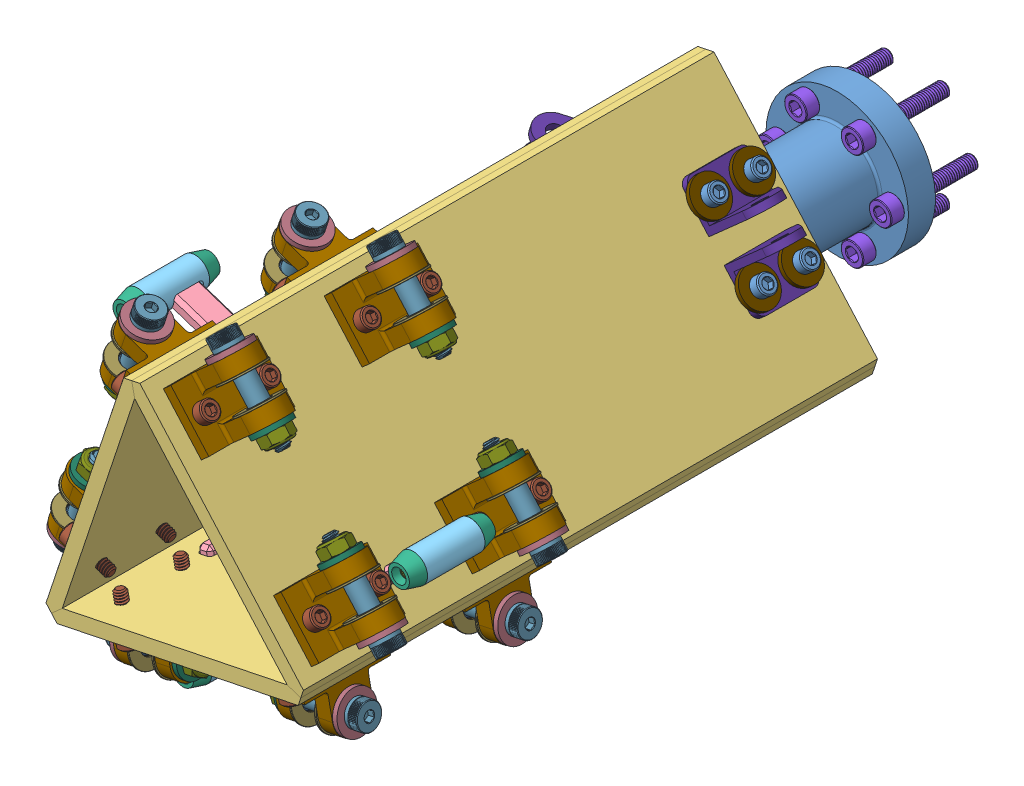
SolidWorks assembly Frame with Tabs and Links, configuration Default. Lengths in mm.
Overall size (158.73 160.79 334.34).
213 component instances, 19 part files, 45 mates.
Components (placement in the parent):
- Frame Assembly (FR)-1: Frame Assembly (FR) [Default] at (-29.1252 -2.2238 -96.7054) size (142.98 145.53 334.34)
  - Mounting Shaft (FR-1)-1: Mounting Shaft (FR-1) [Default] at (1.4417 19.9516 -46.3155) size (63 63 76)
  - Triangle (FR-2)-1: Triangle (FR-2) [Default] at (1.4417 19.9516 10.6845) x (0.979489 0.201496 0) z (0 0 1) size (101.6 87.99 6.35)
  - Frame Plate (FR-3)-1: Frame Plate (FR-3) [Default] at (23.3658 39.4335 112.2845) x (0.664246 -0.747514 0) z (0.747514 0.664246 0) size (112.6 254 6.35)
  - Frame Plate (FR-3)-2: Frame Plate (FR-3) [Default] at (-26.3922 29.1975 112.2845) x (0.315244 0.949011 0) z (-0.949011 0.315244 0) size (112.6 254 6.35)
  - Frame Plate (FR-3)-3: Frame Plate (FR-3) [Default] at (7.3514 -8.7763 112.2845) x (-0.979489 -0.201496 0) z (0.201496 -0.979489 0) size (112.6 254 6.35)
  - Bump Stop Assembly (BS)-1: Bump Stop Assembly (BS) [Default] at (-48.4512 43.2804 219.086) x (-0.315244 -0.949011 0) z (0.949011 -0.315244 0) size (14.59 38.1 45.39)
    - Bump Stop Bar (BS-1)-1: Bump Stop Bar (BS-1) [Default] at (-30.3388 9.583 -9.5512) size (6.22 12.57 38.1)
    - Bump Stop Rod (BS-2)-1: Bump Stop Rod (BS-2) [Default] at (-30.3388 18.7905 -9.5512) x (0 0 1) z (0 -1 0) size (12.7 12.7 25.4)
    - Bump Stop Bumper (MMC 9540K842)-1: Bump Stop Bumper (MMC 9540K842) [Default] at (-30.3388 18.7905 -9.5512) x (0.986856 0 -0.161605) z (0 1 0) size (12.7 12.7 6.35)
    - Bump Stop Bumper (MMC 9540K842)-2: Bump Stop Bumper (MMC 9540K842) [Default] at (-30.3388 -6.6095 -9.5512) x (1 0 0) z (0 -1 0) size (12.7 12.7 6.35)
    - Bump Stop Bolt (MMC 91306A256)-1: Bump Stop Bolt (MMC 91306A256) [91306A256] at (-30.3388 22.8482 -9.5512) x (1 0 0) z (0 1 0) size (6.05 6.05 8.36)
    - Bump Stop Bolt (MMC 91306A256)-2: Bump Stop Bolt (MMC 91306A256) [91306A256] at (-30.3388 -10.6671 -9.5512) x (1 0 0) z (0 -1 0) size (6.05 6.05 8.36)
  - Bump Stop Assembly (BS)-2: Bump Stop Assembly (BS) [Default] at (46.5915 51.4956 219.086) x (-0.664246 0.747514 0) z (-0.747514 -0.664246 0) size (14.59 38.1 45.39)
    - Bump Stop Bar (BS-1)-1: Bump Stop Bar (BS-1) [Default] at (-30.3388 9.583 -9.5512) size (6.22 12.57 38.1)
    - Bump Stop Rod (BS-2)-1: Bump Stop Rod (BS-2) [Default] at (-30.3388 18.7905 -9.5512) x (0 0 1) z (0 -1 0) size (12.7 12.7 25.4)
    - Bump Stop Bumper (MMC 9540K842)-1: Bump Stop Bumper (MMC 9540K842) [Default] at (-30.3388 18.7905 -9.5512) x (0.986856 0 -0.161605) z (0 1 0) size (12.7 12.7 6.35)
    - Bump Stop Bumper (MMC 9540K842)-2: Bump Stop Bumper (MMC 9540K842) [Default] at (-30.3388 -6.6095 -9.5512) x (1 0 0) z (0 -1 0) size (12.7 12.7 6.35)
    - Bump Stop Bolt (MMC 91306A256)-1: Bump Stop Bolt (MMC 91306A256) [91306A256] at (-30.3388 22.8482 -9.5512) x (1 0 0) z (0 1 0) size (6.05 6.05 8.36)
    - Bump Stop Bolt (MMC 91306A256)-2: Bump Stop Bolt (MMC 91306A256) [91306A256] at (-30.3388 -10.6671 -9.5512) x (1 0 0) z (0 -1 0) size (6.05 6.05 8.36)
  - Bump Stop Assembly (BS)-3: Bump Stop Assembly (BS) [Default] at (6.1847 -34.9214 219.086) x (0.979489 0.201496 0) z (-0.201496 0.979489 0) size (14.59 38.1 45.39)
    - Bump Stop Bar (BS-1)-1: Bump Stop Bar (BS-1) [Default] at (-30.3388 9.583 -9.5512) size (6.22 12.57 38.1)
    - Bump Stop Rod (BS-2)-1: Bump Stop Rod (BS-2) [Default] at (-30.3388 18.7905 -9.5512) x (0 0 1) z (0 -1 0) size (12.7 12.7 25.4)
    - Bump Stop Bumper (MMC 9540K842)-1: Bump Stop Bumper (MMC 9540K842) [Default] at (-30.3388 18.7905 -9.5512) x (0.986856 0 -0.161605) z (0 1 0) size (12.7 12.7 6.35)
    - Bump Stop Bumper (MMC 9540K842)-2: Bump Stop Bumper (MMC 9540K842) [Default] at (-30.3388 -6.6095 -9.5512) x (1 0 0) z (0 -1 0) size (12.7 12.7 6.35)
    - Bump Stop Bolt (MMC 91306A256)-1: Bump Stop Bolt (MMC 91306A256) [91306A256] at (-30.3388 22.8482 -9.5512) x (1 0 0) z (0 1 0) size (6.05 6.05 8.36)
    - Bump Stop Bolt (MMC 91306A256)-2: Bump Stop Bolt (MMC 91306A256) [91306A256] at (-30.3388 -10.6671 -9.5512) x (1 0 0) z (0 -1 0) size (6.05 6.05 8.36)
  - Bolt Circle Bolts (MMC 91290A334)-1: Bolt Circle Bolts (MMC 91290A334) [91290A334] at (26.4417 19.9516 -69.3155) x (-0.923728 -0.383049 0) z (0 0 -1) size (10 10 41.63)
  - Bolt Circle Bolts (MMC 91290A334)-2: Bolt Circle Bolts (MMC 91290A334) [91290A334] at (-23.5583 19.9516 -69.3155) x (-0.923728 -0.383049 0) z (0 0 -1) size (10 10 41.63)
  - Bolt Circle Bolts (MMC 91290A334)-3: Bolt Circle Bolts (MMC 91290A334) [91290A334] at (-11.0583 41.6022 -69.3155) x (-0.923728 -0.383049 0) z (0 0 -1) size (10 10 41.63)
  - Bolt Circle Bolts (MMC 91290A334)-4: Bolt Circle Bolts (MMC 91290A334) [91290A334] at (-11.0583 -1.6991 -69.3155) x (-0.923728 -0.383049 0) z (0 0 -1) size (10 10 41.63)
  - Bolt Circle Bolts (MMC 91290A334)-5: Bolt Circle Bolts (MMC 91290A334) [91290A334] at (13.9417 -1.6991 -69.3155) x (-0.923728 -0.383049 0) z (0 0 -1) size (10 10 41.63)
  - Bolt Circle Bolts (MMC 91290A334)-6: Bolt Circle Bolts (MMC 91290A334) [91290A334] at (13.9417 41.6022 -69.3155) x (-0.923728 -0.383049 0) z (0 0 -1) size (10 10 41.63)
- Tab Assembly-1: Tab Assembly [Default] at (-78.7846 -22.708 74.7515) x (-0.315244 -0.949011 0) z (-0.949011 0.315244 0) size (42.53 38.1 36.71)
  - Link Tab (LK-1)-1: Link Tab (LK-1) [Default] at (-17.7971 -3.9275 -0.0689) size (25.27 38.1 24.26)
  - Tab Sleeve Bushing (igus TSI-0506-04)-1: Tab Sleeve Bushing (igus TSI-0506-04) [Default] at (-5.1606 -3.9275 15.2981) x (0 0 1) z (-1 0 0) size (9.53 9.53 6.35)
  - Tab Sleeve Bushing (igus TSI-0506-04)-2: Tab Sleeve Bushing (igus TSI-0506-04) [Default] at (-30.4336 -3.9275 15.2981) x (0 -0.924225 -0.381849) z (1 0 0) size (9.53 9.53 6.35)
  - Tab Bolts (MMC 91251A244)-1: Tab Bolts (MMC 91251A244) [91251A244] at (-17.7971 9.4075 -11.4989) x (-0.923728 -0.383049 0) z (0 0 -1) size (7.92 7.92 21.32)
  - Tab Bolts (MMC 91251A244)-2: Tab Bolts (MMC 91251A244) [91251A244] at (-17.7971 -17.2625 -11.4989) x (-0.923728 -0.383049 0) z (0 0 -1) size (7.92 7.92 21.32)
  - Linkage Thrust Bearing (MSC 06455364)-1: Linkage Thrust Bearing (MSC 06455364) [Default] at (-12.5584 -3.9275 15.2981) x (0 0 -1) z (1 0 0) size (19.05 19.05 0.79)
  - Linkage Thrust Bearing (MSC 06455364)-2: Linkage Thrust Bearing (MSC 06455364) [Default] at (-23.8296 -3.9275 15.2981) x (0 0 -1) z (1 0 0) size (19.05 19.05 0.79)
  - SAE 0.3125 Washer (MMC 96659A107)-1: SAE 0.3125 Washer (MMC 96659A107) [96659A107] at (-3.1286 -3.9275 15.2981) x (0 1 0) z (0 0 1) size (17.46 2.03 17.46)
  - Link Pivot Shoulder Bolt (MMC 91259A583)-1: Link Pivot Shoulder Bolt (MMC 91259A583) [91259A583] at (-3.1286 -3.9275 15.2981) x (0 -1 0) z (0 0 1) size (11.11 42.53 11.11)
  - SAE 025 Washer (MMC 91083A029)-1: SAE 025 Washer (MMC 91083A029) [91083A029] at (-32.4656 -3.9275 15.2981) size (2.03 15.88 15.88)
  - Pivot Nylok (MMC 94945A205)-1: Pivot Nylok (MMC 94945A205) [94945A205] at (-32.4656 -3.9275 15.2981) x (0 1 0) z (0 0 1) size (11.11 5.35 12.83)
- Tab Assembly-2: Tab Assembly [Default] at (-44.4336 80.7024 66.8966) x (0.315244 0.949011 0) z (-0.949011 0.315244 0) size (42.53 38.1 36.71)
  - Link Tab (LK-1)-1: Link Tab (LK-1) [Default] at (-17.7971 -3.9275 -0.0689) size (25.27 38.1 24.26)
  - Tab Sleeve Bushing (igus TSI-0506-04)-1: Tab Sleeve Bushing (igus TSI-0506-04) [Default] at (-5.1606 -3.9275 15.2981) x (0 0 1) z (-1 0 0) size (9.53 9.53 6.35)
  - Tab Sleeve Bushing (igus TSI-0506-04)-2: Tab Sleeve Bushing (igus TSI-0506-04) [Default] at (-30.4336 -3.9275 15.2981) x (0 -0.924225 -0.381849) z (1 0 0) size (9.53 9.53 6.35)
  - Tab Bolts (MMC 91251A244)-1: Tab Bolts (MMC 91251A244) [91251A244] at (-17.7971 9.4075 -11.4989) x (-0.923728 -0.383049 0) z (0 0 -1) size (7.92 7.92 21.32)
  - Tab Bolts (MMC 91251A244)-2: Tab Bolts (MMC 91251A244) [91251A244] at (-17.7971 -17.2625 -11.4989) x (-0.923728 -0.383049 0) z (0 0 -1) size (7.92 7.92 21.32)
  - Linkage Thrust Bearing (MSC 06455364)-1: Linkage Thrust Bearing (MSC 06455364) [Default] at (-12.5584 -3.9275 15.2981) x (0 0 -1) z (1 0 0) size (19.05 19.05 0.79)
  - Linkage Thrust Bearing (MSC 06455364)-2: Linkage Thrust Bearing (MSC 06455364) [Default] at (-23.8296 -3.9275 15.2981) x (0 0 -1) z (1 0 0) size (19.05 19.05 0.79)
  - SAE 0.3125 Washer (MMC 96659A107)-1: SAE 0.3125 Washer (MMC 96659A107) [96659A107] at (-3.1286 -3.9275 15.2981) x (0 1 0) z (0 0 1) size (17.46 2.03 17.46)
  - Link Pivot Shoulder Bolt (MMC 91259A583)-1: Link Pivot Shoulder Bolt (MMC 91259A583) [91259A583] at (-3.1286 -3.9275 15.2981) x (0 -1 0) z (0 0 1) size (11.11 42.53 11.11)
  - SAE 025 Washer (MMC 91083A029)-1: SAE 025 Washer (MMC 91083A029) [91083A029] at (-32.4656 -3.9275 15.2981) size (2.03 15.88 15.88)
  - Pivot Nylok (MMC 94945A205)-1: Pivot Nylok (MMC 94945A205) [94945A205] at (-32.4656 -3.9275 15.2981) x (0 1 0) z (0 0 1) size (11.11 5.35 12.83)
- Tab Assembly-3: Tab Assembly [Default] at (-44.4336 80.7024 138.0166) x (0.315244 0.949011 0) z (-0.949011 0.315244 0) size (42.53 38.1 36.71)
  - Link Tab (LK-1)-1: Link Tab (LK-1) [Default] at (-17.7971 -3.9275 -0.0689) size (25.27 38.1 24.26)
  - Tab Sleeve Bushing (igus TSI-0506-04)-1: Tab Sleeve Bushing (igus TSI-0506-04) [Default] at (-5.1606 -3.9275 15.2981) x (0 0 1) z (-1 0 0) size (9.53 9.53 6.35)
  - Tab Sleeve Bushing (igus TSI-0506-04)-2: Tab Sleeve Bushing (igus TSI-0506-04) [Default] at (-30.4336 -3.9275 15.2981) x (0 -0.924225 -0.381849) z (1 0 0) size (9.53 9.53 6.35)
  - Tab Bolts (MMC 91251A244)-1: Tab Bolts (MMC 91251A244) [91251A244] at (-17.7971 9.4075 -11.4989) x (-0.923728 -0.383049 0) z (0 0 -1) size (7.92 7.92 21.32)
  - Tab Bolts (MMC 91251A244)-2: Tab Bolts (MMC 91251A244) [91251A244] at (-17.7971 -17.2625 -11.4989) x (-0.923728 -0.383049 0) z (0 0 -1) size (7.92 7.92 21.32)
  - Linkage Thrust Bearing (MSC 06455364)-1: Linkage Thrust Bearing (MSC 06455364) [Default] at (-12.5584 -3.9275 15.2981) x (0 0 -1) z (1 0 0) size (19.05 19.05 0.79)
  - Linkage Thrust Bearing (MSC 06455364)-2: Linkage Thrust Bearing (MSC 06455364) [Default] at (-23.8296 -3.9275 15.2981) x (0 0 -1) z (1 0 0) size (19.05 19.05 0.79)
  - SAE 0.3125 Washer (MMC 96659A107)-1: SAE 0.3125 Washer (MMC 96659A107) [96659A107] at (-3.1286 -3.9275 15.2981) x (0 1 0) z (0 0 1) size (17.46 2.03 17.46)
  - Link Pivot Shoulder Bolt (MMC 91259A583)-1: Link Pivot Shoulder Bolt (MMC 91259A583) [91259A583] at (-3.1286 -3.9275 15.2981) x (0 -1 0) z (0 0 1) size (11.11 42.53 11.11)
  - SAE 025 Washer (MMC 91083A029)-1: SAE 025 Washer (MMC 91083A029) [91083A029] at (-32.4656 -3.9275 15.2981) size (2.03 15.88 15.88)
  - Pivot Nylok (MMC 94945A205)-1: Pivot Nylok (MMC 94945A205) [94945A205] at (-32.4656 -3.9275 15.2981) x (0 1 0) z (0 0 1) size (11.11 5.35 12.83)
- Tab Assembly-4: Tab Assembly [Default] at (-78.7846 -22.708 145.8715) x (-0.315244 -0.949011 0) z (-0.949011 0.315244 0) size (42.53 38.1 36.71)
  - Link Tab (LK-1)-1: Link Tab (LK-1) [Default] at (-17.7971 -3.9275 -0.0689) size (25.27 38.1 24.26)
  - Tab Sleeve Bushing (igus TSI-0506-04)-1: Tab Sleeve Bushing (igus TSI-0506-04) [Default] at (-5.1606 -3.9275 15.2981) x (0 0 1) z (-1 0 0) size (9.53 9.53 6.35)
  - Tab Sleeve Bushing (igus TSI-0506-04)-2: Tab Sleeve Bushing (igus TSI-0506-04) [Default] at (-30.4336 -3.9275 15.2981) x (0 -0.924225 -0.381849) z (1 0 0) size (9.53 9.53 6.35)
  - Tab Bolts (MMC 91251A244)-1: Tab Bolts (MMC 91251A244) [91251A244] at (-17.7971 9.4075 -11.4989) x (-0.923728 -0.383049 0) z (0 0 -1) size (7.92 7.92 21.32)
  - Tab Bolts (MMC 91251A244)-2: Tab Bolts (MMC 91251A244) [91251A244] at (-17.7971 -17.2625 -11.4989) x (-0.923728 -0.383049 0) z (0 0 -1) size (7.92 7.92 21.32)
  - Linkage Thrust Bearing (MSC 06455364)-1: Linkage Thrust Bearing (MSC 06455364) [Default] at (-12.5584 -3.9275 15.2981) x (0 0 -1) z (1 0 0) size (19.05 19.05 0.79)
  - Linkage Thrust Bearing (MSC 06455364)-2: Linkage Thrust Bearing (MSC 06455364) [Default] at (-23.8296 -3.9275 15.2981) x (0 0 -1) z (1 0 0) size (19.05 19.05 0.79)
  - SAE 0.3125 Washer (MMC 96659A107)-1: SAE 0.3125 Washer (MMC 96659A107) [96659A107] at (-3.1286 -3.9275 15.2981) x (0 1 0) z (0 0 1) size (17.46 2.03 17.46)
  - Link Pivot Shoulder Bolt (MMC 91259A583)-1: Link Pivot Shoulder Bolt (MMC 91259A583) [91259A583] at (-3.1286 -3.9275 15.2981) x (0 -1 0) z (0 0 1) size (11.11 42.53 11.11)
  - SAE 025 Washer (MMC 91083A029)-1: SAE 025 Washer (MMC 91083A029) [91083A029] at (-32.4656 -3.9275 15.2981) size (2.03 15.88 15.88)
  - Pivot Nylok (MMC 94945A205)-1: Pivot Nylok (MMC 94945A205) [94945A205] at (-32.4656 -3.9275 15.2981) x (0 1 0) z (0 0 1) size (11.11 5.35 12.83)
- Tab Assembly-5: Tab Assembly [Default] at (35.2291 0.7464 66.8966) x (0.664246 -0.747514 0) z (0.747514 0.664246 0) size (42.53 38.1 36.71)
  - Link Tab (LK-1)-1: Link Tab (LK-1) [Default] at (-17.7971 -3.9275 -0.0689) size (25.27 38.1 24.26)
  - Tab Sleeve Bushing (igus TSI-0506-04)-1: Tab Sleeve Bushing (igus TSI-0506-04) [Default] at (-5.1606 -3.9275 15.2981) x (0 0 1) z (-1 0 0) size (9.53 9.53 6.35)
  - Tab Sleeve Bushing (igus TSI-0506-04)-2: Tab Sleeve Bushing (igus TSI-0506-04) [Default] at (-30.4336 -3.9275 15.2981) x (0 -0.924225 -0.381849) z (1 0 0) size (9.53 9.53 6.35)
  - Tab Bolts (MMC 91251A244)-1: Tab Bolts (MMC 91251A244) [91251A244] at (-17.7971 9.4075 -11.4989) x (-0.923728 -0.383049 0) z (0 0 -1) size (7.92 7.92 21.32)
  - Tab Bolts (MMC 91251A244)-2: Tab Bolts (MMC 91251A244) [91251A244] at (-17.7971 -17.2625 -11.4989) x (-0.923728 -0.383049 0) z (0 0 -1) size (7.92 7.92 21.32)
  - Linkage Thrust Bearing (MSC 06455364)-1: Linkage Thrust Bearing (MSC 06455364) [Default] at (-12.5584 -3.9275 15.2981) x (0 0 -1) z (1 0 0) size (19.05 19.05 0.79)
  - Linkage Thrust Bearing (MSC 06455364)-2: Linkage Thrust Bearing (MSC 06455364) [Default] at (-23.8296 -3.9275 15.2981) x (0 0 -1) z (1 0 0) size (19.05 19.05 0.79)
  - SAE 0.3125 Washer (MMC 96659A107)-1: SAE 0.3125 Washer (MMC 96659A107) [96659A107] at (-3.1286 -3.9275 15.2981) x (0 1 0) z (0 0 1) size (17.46 2.03 17.46)
  - Link Pivot Shoulder Bolt (MMC 91259A583)-1: Link Pivot Shoulder Bolt (MMC 91259A583) [91259A583] at (-3.1286 -3.9275 15.2981) x (0 -1 0) z (0 0 1) size (11.11 42.53 11.11)
  - SAE 025 Washer (MMC 91083A029)-1: SAE 025 Washer (MMC 91083A029) [91083A029] at (-32.4656 -3.9275 15.2981) size (2.03 15.88 15.88)
  - Pivot Nylok (MMC 94945A205)-1: Pivot Nylok (MMC 94945A205) [94945A205] at (-32.4656 -3.9275 15.2981) x (0 1 0) z (0 0 1) size (11.11 5.35 12.83)
- Tab Assembly-6: Tab Assembly [Default] at (-37.1514 82.2005 74.7515) x (-0.664246 0.747514 0) z (0.747514 0.664246 0) size (42.53 38.1 36.71)
  - Link Tab (LK-1)-1: Link Tab (LK-1) [Default] at (-17.7971 -3.9275 -0.0689) size (25.27 38.1 24.26)
  - Tab Sleeve Bushing (igus TSI-0506-04)-1: Tab Sleeve Bushing (igus TSI-0506-04) [Default] at (-5.1606 -3.9275 15.2981) x (0 0 1) z (-1 0 0) size (9.53 9.53 6.35)
  - Tab Sleeve Bushing (igus TSI-0506-04)-2: Tab Sleeve Bushing (igus TSI-0506-04) [Default] at (-30.4336 -3.9275 15.2981) x (0 -0.924225 -0.381849) z (1 0 0) size (9.53 9.53 6.35)
  - Tab Bolts (MMC 91251A244)-1: Tab Bolts (MMC 91251A244) [91251A244] at (-17.7971 9.4075 -11.4989) x (-0.923728 -0.383049 0) z (0 0 -1) size (7.92 7.92 21.32)
  - Tab Bolts (MMC 91251A244)-2: Tab Bolts (MMC 91251A244) [91251A244] at (-17.7971 -17.2625 -11.4989) x (-0.923728 -0.383049 0) z (0 0 -1) size (7.92 7.92 21.32)
  - Linkage Thrust Bearing (MSC 06455364)-1: Linkage Thrust Bearing (MSC 06455364) [Default] at (-12.5584 -3.9275 15.2981) x (0 0 -1) z (1 0 0) size (19.05 19.05 0.79)
  - Linkage Thrust Bearing (MSC 06455364)-2: Linkage Thrust Bearing (MSC 06455364) [Default] at (-23.8296 -3.9275 15.2981) x (0 0 -1) z (1 0 0) size (19.05 19.05 0.79)
  - SAE 0.3125 Washer (MMC 96659A107)-1: SAE 0.3125 Washer (MMC 96659A107) [96659A107] at (-3.1286 -3.9275 15.2981) x (0 1 0) z (0 0 1) size (17.46 2.03 17.46)
  - Link Pivot Shoulder Bolt (MMC 91259A583)-1: Link Pivot Shoulder Bolt (MMC 91259A583) [91259A583] at (-3.1286 -3.9275 15.2981) x (0 -1 0) z (0 0 1) size (11.11 42.53 11.11)
  - SAE 025 Washer (MMC 91083A029)-1: SAE 025 Washer (MMC 91083A029) [91083A029] at (-32.4656 -3.9275 15.2981) size (2.03 15.88 15.88)
  - Pivot Nylok (MMC 94945A205)-1: Pivot Nylok (MMC 94945A205) [94945A205] at (-32.4656 -3.9275 15.2981) x (0 1 0) z (0 0 1) size (11.11 5.35 12.83)
- Tab Assembly-7: Tab Assembly [Default] at (35.2291 0.7464 138.0166) x (0.664246 -0.747514 0) z (0.747514 0.664246 0) size (42.53 38.1 36.71)
  - Link Tab (LK-1)-1: Link Tab (LK-1) [Default] at (-17.7971 -3.9275 -0.0689) size (25.27 38.1 24.26)
  - Tab Sleeve Bushing (igus TSI-0506-04)-1: Tab Sleeve Bushing (igus TSI-0506-04) [Default] at (-5.1606 -3.9275 15.2981) x (0 0 1) z (-1 0 0) size (9.53 9.53 6.35)
  - Tab Sleeve Bushing (igus TSI-0506-04)-2: Tab Sleeve Bushing (igus TSI-0506-04) [Default] at (-30.4336 -3.9275 15.2981) x (0 -0.924225 -0.381849) z (1 0 0) size (9.53 9.53 6.35)
  - Tab Bolts (MMC 91251A244)-1: Tab Bolts (MMC 91251A244) [91251A244] at (-17.7971 9.4075 -11.4989) x (-0.923728 -0.383049 0) z (0 0 -1) size (7.92 7.92 21.32)
  - Tab Bolts (MMC 91251A244)-2: Tab Bolts (MMC 91251A244) [91251A244] at (-17.7971 -17.2625 -11.4989) x (-0.923728 -0.383049 0) z (0 0 -1) size (7.92 7.92 21.32)
  - Linkage Thrust Bearing (MSC 06455364)-1: Linkage Thrust Bearing (MSC 06455364) [Default] at (-12.5584 -3.9275 15.2981) x (0 0 -1) z (1 0 0) size (19.05 19.05 0.79)
  - Linkage Thrust Bearing (MSC 06455364)-2: Linkage Thrust Bearing (MSC 06455364) [Default] at (-23.8296 -3.9275 15.2981) x (0 0 -1) z (1 0 0) size (19.05 19.05 0.79)
  - SAE 0.3125 Washer (MMC 96659A107)-1: SAE 0.3125 Washer (MMC 96659A107) [96659A107] at (-3.1286 -3.9275 15.2981) x (0 1 0) z (0 0 1) size (17.46 2.03 17.46)
  - Link Pivot Shoulder Bolt (MMC 91259A583)-1: Link Pivot Shoulder Bolt (MMC 91259A583) [91259A583] at (-3.1286 -3.9275 15.2981) x (0 -1 0) z (0 0 1) size (11.11 42.53 11.11)
  - SAE 025 Washer (MMC 91083A029)-1: SAE 025 Washer (MMC 91083A029) [91083A029] at (-32.4656 -3.9275 15.2981) size (2.03 15.88 15.88)
  - Pivot Nylok (MMC 94945A205)-1: Pivot Nylok (MMC 94945A205) [94945A205] at (-32.4656 -3.9275 15.2981) x (0 1 0) z (0 0 1) size (11.11 5.35 12.83)
- Tab Assembly-8: Tab Assembly [Default] at (-37.1514 82.2005 145.8715) x (-0.664246 0.747514 0) z (0.747514 0.664246 0) size (42.53 38.1 36.71)
  - Link Tab (LK-1)-1: Link Tab (LK-1) [Default] at (-17.7971 -3.9275 -0.0689) size (25.27 38.1 24.26)
  - Tab Sleeve Bushing (igus TSI-0506-04)-1: Tab Sleeve Bushing (igus TSI-0506-04) [Default] at (-5.1606 -3.9275 15.2981) x (0 0 1) z (-1 0 0) size (9.53 9.53 6.35)
  - Tab Sleeve Bushing (igus TSI-0506-04)-2: Tab Sleeve Bushing (igus TSI-0506-04) [Default] at (-30.4336 -3.9275 15.2981) x (0 -0.924225 -0.381849) z (1 0 0) size (9.53 9.53 6.35)
  - Tab Bolts (MMC 91251A244)-1: Tab Bolts (MMC 91251A244) [91251A244] at (-17.7971 9.4075 -11.4989) x (-0.923728 -0.383049 0) z (0 0 -1) size (7.92 7.92 21.32)
  - Tab Bolts (MMC 91251A244)-2: Tab Bolts (MMC 91251A244) [91251A244] at (-17.7971 -17.2625 -11.4989) x (-0.923728 -0.383049 0) z (0 0 -1) size (7.92 7.92 21.32)
  - Linkage Thrust Bearing (MSC 06455364)-1: Linkage Thrust Bearing (MSC 06455364) [Default] at (-12.5584 -3.9275 15.2981) x (0 0 -1) z (1 0 0) size (19.05 19.05 0.79)
  - Linkage Thrust Bearing (MSC 06455364)-2: Linkage Thrust Bearing (MSC 06455364) [Default] at (-23.8296 -3.9275 15.2981) x (0 0 -1) z (1 0 0) size (19.05 19.05 0.79)
  - SAE 0.3125 Washer (MMC 96659A107)-1: SAE 0.3125 Washer (MMC 96659A107) [96659A107] at (-3.1286 -3.9275 15.2981) x (0 1 0) z (0 0 1) size (17.46 2.03 17.46)
  - Link Pivot Shoulder Bolt (MMC 91259A583)-1: Link Pivot Shoulder Bolt (MMC 91259A583) [91259A583] at (-3.1286 -3.9275 15.2981) x (0 -1 0) z (0 0 1) size (11.11 42.53 11.11)
  - SAE 025 Washer (MMC 91083A029)-1: SAE 025 Washer (MMC 91083A029) [91083A029] at (-32.4656 -3.9275 15.2981) size (2.03 15.88 15.88)
  - Pivot Nylok (MMC 94945A205)-1: Pivot Nylok (MMC 94945A205) [94945A205] at (-32.4656 -3.9275 15.2981) x (0 1 0) z (0 0 1) size (11.11 5.35 12.83)
- Tab Assembly-9: Tab Assembly [Default] at (32.8854 -6.3091 145.8715) x (0.979489 0.201496 0) z (0.201496 -0.979489 0) size (42.53 38.1 36.71)
  - Link Tab (LK-1)-1: Link Tab (LK-1) [Default] at (-17.7971 -3.9275 -0.0689) size (25.27 38.1 24.26)
  - Tab Sleeve Bushing (igus TSI-0506-04)-1: Tab Sleeve Bushing (igus TSI-0506-04) [Default] at (-5.1606 -3.9275 15.2981) x (0 0 1) z (-1 0 0) size (9.53 9.53 6.35)
  - Tab Sleeve Bushing (igus TSI-0506-04)-2: Tab Sleeve Bushing (igus TSI-0506-04) [Default] at (-30.4336 -3.9275 15.2981) x (0 -0.924225 -0.381849) z (1 0 0) size (9.53 9.53 6.35)
  - Tab Bolts (MMC 91251A244)-1: Tab Bolts (MMC 91251A244) [91251A244] at (-17.7971 9.4075 -11.4989) x (-0.923728 -0.383049 0) z (0 0 -1) size (7.92 7.92 21.32)
  - Tab Bolts (MMC 91251A244)-2: Tab Bolts (MMC 91251A244) [91251A244] at (-17.7971 -17.2625 -11.4989) x (-0.923728 -0.383049 0) z (0 0 -1) size (7.92 7.92 21.32)
  - Linkage Thrust Bearing (MSC 06455364)-1: Linkage Thrust Bearing (MSC 06455364) [Default] at (-12.5584 -3.9275 15.2981) x (0 0 -1) z (1 0 0) size (19.05 19.05 0.79)
  - Linkage Thrust Bearing (MSC 06455364)-2: Linkage Thrust Bearing (MSC 06455364) [Default] at (-23.8296 -3.9275 15.2981) x (0 0 -1) z (1 0 0) size (19.05 19.05 0.79)
  - SAE 0.3125 Washer (MMC 96659A107)-1: SAE 0.3125 Washer (MMC 96659A107) [96659A107] at (-3.1286 -3.9275 15.2981) x (0 1 0) z (0 0 1) size (17.46 2.03 17.46)
  - Link Pivot Shoulder Bolt (MMC 91259A583)-1: Link Pivot Shoulder Bolt (MMC 91259A583) [91259A583] at (-3.1286 -3.9275 15.2981) x (0 -1 0) z (0 0 1) size (11.11 42.53 11.11)
  - SAE 025 Washer (MMC 91083A029)-1: SAE 025 Washer (MMC 91083A029) [91083A029] at (-32.4656 -3.9275 15.2981) size (2.03 15.88 15.88)
  - Pivot Nylok (MMC 94945A205)-1: Pivot Nylok (MMC 94945A205) [94945A205] at (-32.4656 -3.9275 15.2981) x (0 1 0) z (0 0 1) size (11.11 5.35 12.83)
- Tab Assembly-10: Tab Assembly [Default] at (-73.8462 -28.2655 66.8966) x (-0.979489 -0.201496 0) z (0.201496 -0.979489 0) size (42.53 38.1 36.71)
  - Link Tab (LK-1)-1: Link Tab (LK-1) [Default] at (-17.7971 -3.9275 -0.0689) size (25.27 38.1 24.26)
  - Tab Sleeve Bushing (igus TSI-0506-04)-1: Tab Sleeve Bushing (igus TSI-0506-04) [Default] at (-5.1606 -3.9275 15.2981) x (0 0 1) z (-1 0 0) size (9.53 9.53 6.35)
  - Tab Sleeve Bushing (igus TSI-0506-04)-2: Tab Sleeve Bushing (igus TSI-0506-04) [Default] at (-30.4336 -3.9275 15.2981) x (0 -0.924225 -0.381849) z (1 0 0) size (9.53 9.53 6.35)
  - Tab Bolts (MMC 91251A244)-1: Tab Bolts (MMC 91251A244) [91251A244] at (-17.7971 9.4075 -11.4989) x (-0.923728 -0.383049 0) z (0 0 -1) size (7.92 7.92 21.32)
  - Tab Bolts (MMC 91251A244)-2: Tab Bolts (MMC 91251A244) [91251A244] at (-17.7971 -17.2625 -11.4989) x (-0.923728 -0.383049 0) z (0 0 -1) size (7.92 7.92 21.32)
  - Linkage Thrust Bearing (MSC 06455364)-1: Linkage Thrust Bearing (MSC 06455364) [Default] at (-12.5584 -3.9275 15.2981) x (0 0 -1) z (1 0 0) size (19.05 19.05 0.79)
  - Linkage Thrust Bearing (MSC 06455364)-2: Linkage Thrust Bearing (MSC 06455364) [Default] at (-23.8296 -3.9275 15.2981) x (0 0 -1) z (1 0 0) size (19.05 19.05 0.79)
  - SAE 0.3125 Washer (MMC 96659A107)-1: SAE 0.3125 Washer (MMC 96659A107) [96659A107] at (-3.1286 -3.9275 15.2981) x (0 1 0) z (0 0 1) size (17.46 2.03 17.46)
  - Link Pivot Shoulder Bolt (MMC 91259A583)-1: Link Pivot Shoulder Bolt (MMC 91259A583) [91259A583] at (-3.1286 -3.9275 15.2981) x (0 -1 0) z (0 0 1) size (11.11 42.53 11.11)
  - SAE 025 Washer (MMC 91083A029)-1: SAE 025 Washer (MMC 91083A029) [91083A029] at (-32.4656 -3.9275 15.2981) size (2.03 15.88 15.88)
  - Pivot Nylok (MMC 94945A205)-1: Pivot Nylok (MMC 94945A205) [94945A205] at (-32.4656 -3.9275 15.2981) x (0 1 0) z (0 0 1) size (11.11 5.35 12.83)
- Tab Assembly-11: Tab Assembly [Default] at (-73.8462 -28.2655 138.0166) x (-0.979489 -0.201496 0) z (0.201496 -0.979489 0) size (42.53 38.1 36.71)
  - Link Tab (LK-1)-1: Link Tab (LK-1) [Default] at (-17.7971 -3.9275 -0.0689) size (25.27 38.1 24.26)
  - Tab Sleeve Bushing (igus TSI-0506-04)-1: Tab Sleeve Bushing (igus TSI-0506-04) [Default] at (-5.1606 -3.9275 15.2981) x (0 0 1) z (-1 0 0) size (9.53 9.53 6.35)
  - Tab Sleeve Bushing (igus TSI-0506-04)-2: Tab Sleeve Bushing (igus TSI-0506-04) [Default] at (-30.4336 -3.9275 15.2981) x (0 -0.924225 -0.381849) z (1 0 0) size (9.53 9.53 6.35)
  - Tab Bolts (MMC 91251A244)-1: Tab Bolts (MMC 91251A244) [91251A244] at (-17.7971 9.4075 -11.4989) x (-0.923728 -0.383049 0) z (0 0 -1) size (7.92 7.92 21.32)
  - Tab Bolts (MMC 91251A244)-2: Tab Bolts (MMC 91251A244) [91251A244] at (-17.7971 -17.2625 -11.4989) x (-0.923728 -0.383049 0) z (0 0 -1) size (7.92 7.92 21.32)
  - Linkage Thrust Bearing (MSC 06455364)-1: Linkage Thrust Bearing (MSC 06455364) [Default] at (-12.5584 -3.9275 15.2981) x (0 0 -1) z (1 0 0) size (19.05 19.05 0.79)
  - Linkage Thrust Bearing (MSC 06455364)-2: Linkage Thrust Bearing (MSC 06455364) [Default] at (-23.8296 -3.9275 15.2981) x (0 0 -1) z (1 0 0) size (19.05 19.05 0.79)
  - SAE 0.3125 Washer (MMC 96659A107)-1: SAE 0.3125 Washer (MMC 96659A107) [96659A107] at (-3.1286 -3.9275 15.2981) x (0 1 0) z (0 0 1) size (17.46 2.03 17.46)
  - Link Pivot Shoulder Bolt (MMC 91259A583)-1: Link Pivot Shoulder Bolt (MMC 91259A583) [91259A583] at (-3.1286 -3.9275 15.2981) x (0 -1 0) z (0 0 1) size (11.11 42.53 11.11)
  - SAE 025 Washer (MMC 91083A029)-1: SAE 025 Washer (MMC 91083A029) [91083A029] at (-32.4656 -3.9275 15.2981) size (2.03 15.88 15.88)
  - Pivot Nylok (MMC 94945A205)-1: Pivot Nylok (MMC 94945A205) [94945A205] at (-32.4656 -3.9275 15.2981) x (0 1 0) z (0 0 1) size (11.11 5.35 12.83)
- Tab Assembly-12: Tab Assembly [Default] at (32.8854 -6.3091 74.7515) x (0.979489 0.201496 0) z (0.201496 -0.979489 0) size (42.53 38.1 36.71)
  - Link Tab (LK-1)-1: Link Tab (LK-1) [Default] at (-17.7971 -3.9275 -0.0689) size (25.27 38.1 24.26)
  - Tab Sleeve Bushing (igus TSI-0506-04)-1: Tab Sleeve Bushing (igus TSI-0506-04) [Default] at (-5.1606 -3.9275 15.2981) x (0 0 1) z (-1 0 0) size (9.53 9.53 6.35)
  - Tab Sleeve Bushing (igus TSI-0506-04)-2: Tab Sleeve Bushing (igus TSI-0506-04) [Default] at (-30.4336 -3.9275 15.2981) x (0 -0.924225 -0.381849) z (1 0 0) size (9.53 9.53 6.35)
  - Tab Bolts (MMC 91251A244)-1: Tab Bolts (MMC 91251A244) [91251A244] at (-17.7971 9.4075 -11.4989) x (-0.923728 -0.383049 0) z (0 0 -1) size (7.92 7.92 21.32)
  - Tab Bolts (MMC 91251A244)-2: Tab Bolts (MMC 91251A244) [91251A244] at (-17.7971 -17.2625 -11.4989) x (-0.923728 -0.383049 0) z (0 0 -1) size (7.92 7.92 21.32)
  - Linkage Thrust Bearing (MSC 06455364)-1: Linkage Thrust Bearing (MSC 06455364) [Default] at (-12.5584 -3.9275 15.2981) x (0 0 -1) z (1 0 0) size (19.05 19.05 0.79)
  - Linkage Thrust Bearing (MSC 06455364)-2: Linkage Thrust Bearing (MSC 06455364) [Default] at (-23.8296 -3.9275 15.2981) x (0 0 -1) z (1 0 0) size (19.05 19.05 0.79)
  - SAE 0.3125 Washer (MMC 96659A107)-1: SAE 0.3125 Washer (MMC 96659A107) [96659A107] at (-3.1286 -3.9275 15.2981) x (0 1 0) z (0 0 1) size (17.46 2.03 17.46)
  - Link Pivot Shoulder Bolt (MMC 91259A583)-1: Link Pivot Shoulder Bolt (MMC 91259A583) [91259A583] at (-3.1286 -3.9275 15.2981) x (0 -1 0) z (0 0 1) size (11.11 42.53 11.11)
  - SAE 025 Washer (MMC 91083A029)-1: SAE 025 Washer (MMC 91083A029) [91083A029] at (-32.4656 -3.9275 15.2981) size (2.03 15.88 15.88)
  - Pivot Nylok (MMC 94945A205)-1: Pivot Nylok (MMC 94945A205) [94945A205] at (-32.4656 -3.9275 15.2981) x (0 1 0) z (0 0 1) size (11.11 5.35 12.83)
- Frame Side Bracket Assembly-1: Frame Side Bracket Assembly [Default] at (-82.4621 -4.4954 -48.6466) x (-0.315244 -0.949011 0) z (0 0 -1) size (50.29 41.41 34.93)
  - Frame Side Brackets (NCM-PC075)-1: Frame Side Brackets (NCM-PC075) [NCM-PC075] at (-38.3587 -9.3003 16.2923) size (50.29 30.23 27.94)
    - NCM-PC075_NCMP-C-Bracket-1: NCM-PC075_NCMP-C-Bracket [075F] at (5.08 0 0) size (20.07 30.23 27.94)
    - NCM-PC075_NCMP-C-Bracket-2: NCM-PC075_NCMP-C-Bracket [075R] at (-5.08 0 0) x (-1 0 0) z (0 0 -1) size (20.07 30.23 27.94)
  - SAE 0.25 Washer (MMC 91083A029)-1: SAE 0.25 Washer (MMC 91083A029) [91083A029] at (-54.6147 -4.2203 6.8943) x (0 -1 0) z (0 0 1) size (2.03 15.88 15.88)
  - SAE 0.25 Washer (MMC 91083A029)-2: SAE 0.25 Washer (MMC 91083A029) [91083A029] at (-54.6147 -4.2203 25.9443) x (0 -1 0) z (0 0 1) size (2.03 15.88 15.88)
  - SAE 0.25 Washer (MMC 91083A029)-3: SAE 0.25 Washer (MMC 91083A029) [91083A029] at (-22.1027 -4.2203 6.8943) x (0 -1 0) z (0 0 1) size (2.03 15.88 15.88)
  - SAE 0.25 Washer (MMC 91083A029)-4: SAE 0.25 Washer (MMC 91083A029) [91083A029] at (-22.1027 -4.2203 25.9443) x (0 -1 0) z (0 0 1) size (2.03 15.88 15.88)
  - Tab Bolt (MMC 91251A244)-1: Tab Bolt (MMC 91251A244) [91251A244] at (-22.1027 -20.0953 25.9443) x (1 0 0) z (0 -1 0) size (7.92 7.92 21.32)
  - Tab Bolt (MMC 91251A244)-2: Tab Bolt (MMC 91251A244) [91251A244] at (-22.1027 -20.0953 6.8943) x (1 0 0) z (0 -1 0) size (7.92 7.92 21.32)
  - Tab Bolt (MMC 91251A244)-3: Tab Bolt (MMC 91251A244) [91251A244] at (-54.6147 -20.0953 25.9443) x (1 0 0) z (0 -1 0) size (7.92 7.92 21.32)
  - Tab Bolt (MMC 91251A244)-4: Tab Bolt (MMC 91251A244) [91251A244] at (-54.6147 -20.0953 6.8943) x (1 0 0) z (0 -1 0) size (7.92 7.92 21.32)
- Frame Side Bracket Assembly-2: Frame Side Bracket Assembly [Default] at (-19.5401 76.2791 -48.6466) x (-0.664246 0.747514 0) z (0 0 -1) size (50.29 41.41 34.93)
  - Frame Side Brackets (NCM-PC075)-1: Frame Side Brackets (NCM-PC075) [NCM-PC075] at (-38.3587 -9.3003 16.2923) size (50.29 30.23 27.94)
    - NCM-PC075_NCMP-C-Bracket-1: NCM-PC075_NCMP-C-Bracket [075F] at (5.08 0 0) size (20.07 30.23 27.94)
    - NCM-PC075_NCMP-C-Bracket-2: NCM-PC075_NCMP-C-Bracket [075R] at (-5.08 0 0) x (-1 0 0) z (0 0 -1) size (20.07 30.23 27.94)
  - SAE 0.25 Washer (MMC 91083A029)-1: SAE 0.25 Washer (MMC 91083A029) [91083A029] at (-54.6147 -4.2203 6.8943) x (0 -1 0) z (0 0 1) size (2.03 15.88 15.88)
  - SAE 0.25 Washer (MMC 91083A029)-2: SAE 0.25 Washer (MMC 91083A029) [91083A029] at (-54.6147 -4.2203 25.9443) x (0 -1 0) z (0 0 1) size (2.03 15.88 15.88)
  - SAE 0.25 Washer (MMC 91083A029)-3: SAE 0.25 Washer (MMC 91083A029) [91083A029] at (-22.1027 -4.2203 6.8943) x (0 -1 0) z (0 0 1) size (2.03 15.88 15.88)
  - SAE 0.25 Washer (MMC 91083A029)-4: SAE 0.25 Washer (MMC 91083A029) [91083A029] at (-22.1027 -4.2203 25.9443) x (0 -1 0) z (0 0 1) size (2.03 15.88 15.88)
  - Tab Bolt (MMC 91251A244)-1: Tab Bolt (MMC 91251A244) [91251A244] at (-22.1027 -20.0953 25.9443) x (1 0 0) z (0 -1 0) size (7.92 7.92 21.32)
  - Tab Bolt (MMC 91251A244)-2: Tab Bolt (MMC 91251A244) [91251A244] at (-22.1027 -20.0953 6.8943) x (1 0 0) z (0 -1 0) size (7.92 7.92 21.32)
  - Tab Bolt (MMC 91251A244)-3: Tab Bolt (MMC 91251A244) [91251A244] at (-54.6147 -20.0953 25.9443) x (1 0 0) z (0 -1 0) size (7.92 7.92 21.32)
  - Tab Bolt (MMC 91251A244)-4: Tab Bolt (MMC 91251A244) [91251A244] at (-54.6147 -20.0953 6.8943) x (1 0 0) z (0 -1 0) size (7.92 7.92 21.32)
- Frame Side Bracket Assembly-3: Frame Side Bracket Assembly [Default] at (18.9517 -18.6003 -48.6466) x (0.979489 0.201496 0) z (0 0 -1) size (50.29 41.41 34.93)
  - Frame Side Brackets (NCM-PC075)-1: Frame Side Brackets (NCM-PC075) [NCM-PC075] at (-38.3587 -9.3003 16.2923) size (50.29 30.23 27.94)
    - NCM-PC075_NCMP-C-Bracket-1: NCM-PC075_NCMP-C-Bracket [075F] at (5.08 0 0) size (20.07 30.23 27.94)
    - NCM-PC075_NCMP-C-Bracket-2: NCM-PC075_NCMP-C-Bracket [075R] at (-5.08 0 0) x (-1 0 0) z (0 0 -1) size (20.07 30.23 27.94)
  - SAE 0.25 Washer (MMC 91083A029)-1: SAE 0.25 Washer (MMC 91083A029) [91083A029] at (-54.6147 -4.2203 6.8943) x (0 -1 0) z (0 0 1) size (2.03 15.88 15.88)
  - SAE 0.25 Washer (MMC 91083A029)-2: SAE 0.25 Washer (MMC 91083A029) [91083A029] at (-54.6147 -4.2203 25.9443) x (0 -1 0) z (0 0 1) size (2.03 15.88 15.88)
  - SAE 0.25 Washer (MMC 91083A029)-3: SAE 0.25 Washer (MMC 91083A029) [91083A029] at (-22.1027 -4.2203 6.8943) x (0 -1 0) z (0 0 1) size (2.03 15.88 15.88)
  - SAE 0.25 Washer (MMC 91083A029)-4: SAE 0.25 Washer (MMC 91083A029) [91083A029] at (-22.1027 -4.2203 25.9443) x (0 -1 0) z (0 0 1) size (2.03 15.88 15.88)
  - Tab Bolt (MMC 91251A244)-1: Tab Bolt (MMC 91251A244) [91251A244] at (-22.1027 -20.0953 25.9443) x (1 0 0) z (0 -1 0) size (7.92 7.92 21.32)
  - Tab Bolt (MMC 91251A244)-2: Tab Bolt (MMC 91251A244) [91251A244] at (-22.1027 -20.0953 6.8943) x (1 0 0) z (0 -1 0) size (7.92 7.92 21.32)
  - Tab Bolt (MMC 91251A244)-3: Tab Bolt (MMC 91251A244) [91251A244] at (-54.6147 -20.0953 25.9443) x (1 0 0) z (0 -1 0) size (7.92 7.92 21.32)
  - Tab Bolt (MMC 91251A244)-4: Tab Bolt (MMC 91251A244) [91251A244] at (-54.6147 -20.0953 6.8943) x (1 0 0) z (0 -1 0) size (7.92 7.92 21.32)
Mates (geometry in assembly coordinates):
- Concentric33: concentric anti-aligned: cylinder of Frame Assembly (FR)-1/Frame Plate (FR-3)-2 through (-67.0825 -7.8419 57.489) axis (-0.949011 0.315244 0) radius 1.905; cylinder of Tab Assembly-1/Tab Bolts (MMC 91251A244)-2 through (-81.907 -2.9175 57.489) axis (0.949011 -0.315244 0) radius 3.9624
- Concentric34: concentric anti-aligned: cylinder of Frame Assembly (FR)-1/Frame Plate (FR-3)-2 through (-67.0825 -7.8419 84.159) axis (-0.949011 0.315244 0) radius 1.905; cylinder of Tab Assembly-1/Tab Bolts (MMC 91251A244)-1 through (-81.907 -2.9175 84.159) axis (0.949011 -0.315244 0) radius 3.9624
- Coincident29: coincident anti-aligned: plane of Frame Assembly (FR)-1/Frame Plate (FR-3)-2 through (-61.5437 28.9755 15.579) normal (-0.949011 0.315244 0); plane of Tab Assembly-1/Link Tab (LK-1)-1 through (-73.1087 -5.8401 70.824) normal (0.949011 -0.315244 0)
- Concentric35: concentric anti-aligned: cylinder of Frame Assembly (FR)-1/Frame Plate (FR-3)-2 through (-43.9524 61.7893 57.489) axis (-0.949011 0.315244 0) radius 1.905; cylinder of Tab Assembly-2/Tab Bolts (MMC 91251A244)-1 through (-58.7769 66.7137 57.489) axis (0.949011 -0.315244 0) radius 3.9624
- Concentric36: concentric anti-aligned: cylinder of Frame Assembly (FR)-1/Frame Plate (FR-3)-2 through (-43.9524 61.7893 84.159) axis (-0.949011 0.315244 0) radius 1.905; cylinder of Tab Assembly-2/Tab Bolts (MMC 91251A244)-2 through (-58.7769 66.7137 84.159) axis (0.949011 -0.315244 0) radius 3.9624
- Coincident30: coincident anti-aligned: plane of Frame Assembly (FR)-1/Frame Plate (FR-3)-2 through (-61.5437 28.9755 15.579) normal (-0.949011 0.315244 0); plane of Tab Assembly-2/Link Tab (LK-1)-1 through (-49.9786 63.7911 70.824) normal (0.949011 -0.315244 0)
- Concentric37: concentric anti-aligned: cylinder of Frame Assembly (FR)-1/Frame Plate (FR-3)-2 through (-67.0825 -7.8419 155.279) axis (-0.949011 0.315244 0) radius 1.905; cylinder of Tab Assembly-4/Tab Bolts (MMC 91251A244)-1 through (-81.907 -2.9175 155.279) axis (0.949011 -0.315244 0) radius 3.9624
- Concentric38: concentric anti-aligned: cylinder of Frame Assembly (FR)-1/Frame Plate (FR-3)-2 through (-67.0825 -7.8419 128.609) axis (-0.949011 0.315244 0) radius 1.905; cylinder of Tab Assembly-4/Tab Bolts (MMC 91251A244)-2 through (-81.907 -2.9175 128.609) axis (0.949011 -0.315244 0) radius 3.9624
- Coincident31: coincident anti-aligned: plane of Frame Assembly (FR)-1/Frame Plate (FR-3)-2 through (-61.5437 28.9755 15.579) normal (-0.949011 0.315244 0); plane of Tab Assembly-4/Link Tab (LK-1)-1 through (-73.1087 -5.8401 141.944) normal (0.949011 -0.315244 0)
- Concentric39: concentric anti-aligned: cylinder of Frame Assembly (FR)-1/Frame Plate (FR-3)-2 through (-43.9524 61.7893 128.609) axis (-0.949011 0.315244 0) radius 1.905; cylinder of Tab Assembly-3/Tab Bolts (MMC 91251A244)-1 through (-58.7769 66.7137 128.609) axis (0.949011 -0.315244 0) radius 3.9624
- Concentric40: concentric anti-aligned: cylinder of Frame Assembly (FR)-1/Frame Plate (FR-3)-2 through (-43.9524 61.7893 155.279) axis (-0.949011 0.315244 0) radius 1.905; cylinder of Tab Assembly-3/Tab Bolts (MMC 91251A244)-2 through (-58.7769 66.7137 155.279) axis (0.949011 -0.315244 0) radius 3.9624
- Coincident32: coincident anti-aligned: plane of Frame Assembly (FR)-1/Frame Plate (FR-3)-2 through (-61.5437 28.9755 15.579) normal (-0.949011 0.315244 0); plane of Tab Assembly-3/Link Tab (LK-1)-1 through (-49.9786 63.7911 141.944) normal (0.949011 -0.315244 0)
- Concentric41: concentric anti-aligned: cylinder of Frame Assembly (FR)-1/Frame Plate (FR-3)-1 through (-30.128 64.6331 57.489) axis (0.747514 0.664246 0) radius 1.905; cylinder of Tab Assembly-6/Tab Bolts (MMC 91251A244)-2 through (-18.4511 75.0093 57.489) axis (-0.747514 -0.664246 0) radius 3.9624
- Concentric42: concentric anti-aligned: cylinder of Frame Assembly (FR)-1/Frame Plate (FR-3)-1 through (-30.128 64.6331 84.159) axis (0.747514 0.664246 0) radius 1.905; cylinder of Tab Assembly-6/Tab Bolts (MMC 91251A244)-1 through (-18.4511 75.0093 84.159) axis (-0.747514 -0.664246 0) radius 3.9624
- Coincident33: coincident anti-aligned: plane of Frame Assembly (FR)-1/Frame Plate (FR-3)-1 through (-1.0127 41.4277 15.579) normal (0.747514 0.664246 0); plane of Tab Assembly-6/Link Tab (LK-1)-1 through (-25.3813 68.8511 70.824) normal (-0.747514 -0.664246 0)
- Concentric43: concentric anti-aligned: cylinder of Frame Assembly (FR)-1/Frame Plate (FR-3)-1 through (-30.128 64.6331 155.279) axis (0.747514 0.664246 0) radius 1.905; cylinder of Tab Assembly-8/Tab Bolts (MMC 91251A244)-1 through (-18.4511 75.0093 155.279) axis (-0.747514 -0.664246 0) radius 3.9624
- Concentric44: concentric anti-aligned: cylinder of Frame Assembly (FR)-1/Frame Plate (FR-3)-1 through (-30.128 64.6331 128.609) axis (0.747514 0.664246 0) radius 1.905; cylinder of Tab Assembly-8/Tab Bolts (MMC 91251A244)-2 through (-18.4511 75.0093 128.609) axis (-0.747514 -0.664246 0) radius 3.9624
- Coincident34: coincident anti-aligned: plane of Frame Assembly (FR)-1/Frame Plate (FR-3)-1 through (-1.0127 41.4277 15.579) normal (0.747514 0.664246 0); plane of Tab Assembly-8/Link Tab (LK-1)-1 through (-25.3813 68.8511 141.944) normal (-0.747514 -0.664246 0)
- Concentric45: concentric anti-aligned: cylinder of Frame Assembly (FR)-1/Frame Plate (FR-3)-1 through (18.6092 9.7863 57.489) axis (0.747514 0.664246 0) radius 1.905; cylinder of Tab Assembly-5/Tab Bolts (MMC 91251A244)-1 through (30.2862 20.1624 57.489) axis (-0.747514 -0.664246 0) radius 3.9624
- Concentric46: concentric anti-aligned: cylinder of Frame Assembly (FR)-1/Frame Plate (FR-3)-1 through (18.6092 9.7863 84.159) axis (0.747514 0.664246 0) radius 1.905; cylinder of Tab Assembly-5/Tab Bolts (MMC 91251A244)-2 through (30.2862 20.1624 84.159) axis (-0.747514 -0.664246 0) radius 3.9624
- Coincident35: coincident anti-aligned: plane of Frame Assembly (FR)-1/Frame Plate (FR-3)-1 through (-1.0127 41.4277 15.579) normal (0.747514 0.664246 0); plane of Tab Assembly-5/Link Tab (LK-1)-1 through (23.356 14.0042 70.824) normal (-0.747514 -0.664246 0)
- Concentric47: concentric anti-aligned: cylinder of Frame Assembly (FR)-1/Frame Plate (FR-3)-1 through (18.6092 9.7863 128.609) axis (0.747514 0.664246 0) radius 1.905; cylinder of Tab Assembly-7/Tab Bolts (MMC 91251A244)-1 through (30.2862 20.1624 128.609) axis (-0.747514 -0.664246 0) radius 3.9624
- Concentric48: concentric anti-aligned: cylinder of Frame Assembly (FR)-1/Frame Plate (FR-3)-1 through (18.6092 9.7863 155.279) axis (0.747514 0.664246 0) radius 1.905; cylinder of Tab Assembly-7/Tab Bolts (MMC 91251A244)-2 through (30.2862 20.1624 155.279) axis (-0.747514 -0.664246 0) radius 3.9624
- Coincident36: coincident anti-aligned: plane of Frame Assembly (FR)-1/Frame Plate (FR-3)-1 through (-1.0127 41.4277 15.579) normal (0.747514 0.664246 0); plane of Tab Assembly-7/Link Tab (LK-1)-1 through (23.356 14.0042 141.944) normal (-0.747514 -0.664246 0)
- Concentric49: concentric anti-aligned: cylinder of Frame Assembly (FR)-1/Frame Plate (FR-3)-3 through (14.1599 -3.6079 57.489) axis (0.201496 -0.979489 0) radius 1.905; cylinder of Tab Assembly-12/Tab Bolts (MMC 91251A244)-2 through (17.3075 -18.9085 57.489) axis (-0.201496 0.979489 0) radius 3.9624
- Concentric50: concentric anti-aligned: cylinder of Frame Assembly (FR)-1/Frame Plate (FR-3)-3 through (14.1599 -3.6079 84.159) axis (0.201496 -0.979489 0) radius 1.905; cylinder of Tab Assembly-12/Tab Bolts (MMC 91251A244)-1 through (17.3075 -18.9085 84.159) axis (-0.201496 0.979489 0) radius 3.9624
- Coincident38: coincident anti-aligned: plane of Frame Assembly (FR)-1/Frame Plate (FR-3)-3 through (-20.4943 -17.2198 15.579) normal (0.201496 -0.979489 0); plane of Tab Assembly-12/Link Tab (LK-1)-1 through (15.4395 -9.8277 70.824) normal (-0.201496 0.979489 0)
- Concentric51: concentric anti-aligned: cylinder of Frame Assembly (FR)-1/Frame Plate (FR-3)-3 through (-57.7075 -18.3922 84.159) axis (0.201496 -0.979489 0) radius 1.905; cylinder of Tab Assembly-10/Tab Bolts (MMC 91251A244)-2 through (-54.5599 -33.6928 84.159) axis (-0.201496 0.979489 0) radius 3.9624
- Concentric52: concentric anti-aligned: cylinder of Frame Assembly (FR)-1/Frame Plate (FR-3)-3 through (-57.7075 -18.3922 57.489) axis (0.201496 -0.979489 0) radius 1.905; cylinder of Tab Assembly-10/Tab Bolts (MMC 91251A244)-1 through (-54.5599 -33.6928 57.489) axis (-0.201496 0.979489 0) radius 3.9624
- Coincident39: coincident anti-aligned: plane of Frame Assembly (FR)-1/Frame Plate (FR-3)-3 through (-20.4943 -17.2198 15.579) normal (0.201496 -0.979489 0); plane of Tab Assembly-10/Link Tab (LK-1)-1 through (-56.428 -24.6119 70.824) normal (-0.201496 0.979489 0)
- Concentric53: concentric anti-aligned: cylinder of Frame Assembly (FR)-1/Frame Plate (FR-3)-3 through (14.1599 -3.6079 128.609) axis (0.201496 -0.979489 0) radius 1.905; cylinder of Tab Assembly-9/Tab Bolts (MMC 91251A244)-2 through (17.3075 -18.9085 128.609) axis (-0.201496 0.979489 0) radius 3.9624
- Concentric54: concentric anti-aligned: cylinder of Frame Assembly (FR)-1/Frame Plate (FR-3)-3 through (14.1599 -3.6079 155.279) axis (0.201496 -0.979489 0) radius 1.905; cylinder of Tab Assembly-9/Tab Bolts (MMC 91251A244)-1 through (17.3075 -18.9085 155.279) axis (-0.201496 0.979489 0) radius 3.9624
- Coincident40: coincident anti-aligned: plane of Frame Assembly (FR)-1/Frame Plate (FR-3)-3 through (-20.4943 -17.2198 15.579) normal (0.201496 -0.979489 0); plane of Tab Assembly-9/Link Tab (LK-1)-1 through (15.4395 -9.8277 141.944) normal (-0.201496 0.979489 0)
- Concentric55: concentric anti-aligned: cylinder of Frame Assembly (FR)-1/Frame Plate (FR-3)-3 through (-57.7075 -18.3922 128.609) axis (0.201496 -0.979489 0) radius 1.905; cylinder of Tab Assembly-11/Tab Bolts (MMC 91251A244)-1 through (-54.5599 -33.6928 128.609) axis (-0.201496 0.979489 0) radius 3.9624
- Coincident41: coincident anti-aligned: plane of Frame Assembly (FR)-1/Frame Plate (FR-3)-3 through (-20.4943 -17.2198 15.579) normal (0.201496 -0.979489 0); plane of Tab Assembly-11/Link Tab (LK-1)-1 through (-56.428 -24.6119 141.944) normal (-0.201496 0.979489 0)
- Concentric56: concentric anti-aligned: cylinder of Frame Assembly (FR)-1/Frame Plate (FR-3)-3 through (-57.7075 -18.3922 155.279) axis (0.201496 -0.979489 0) radius 1.905; cylinder of Tab Assembly-11/Tab Bolts (MMC 91251A244)-2 through (-54.5599 -33.6928 155.279) axis (-0.201496 0.979489 0) radius 3.9624
- Concentric57: concentric anti-aligned: cylinder of Frame Assembly (FR)-1/Frame Plate (FR-3)-2 through (-50.3928 42.4008 -74.591) axis (-0.949011 0.315244 0) radius 1.905; cylinder of Frame Side Bracket Assembly-1/Tab Bolt (MMC 91251A244)-3 through (-65.82 47.5254 -74.591) axis (0.949011 -0.315244 0) radius 3.9624
- Concentric58: concentric anti-aligned: cylinder of Frame Assembly (FR)-1/Frame Plate (FR-3)-2 through (-60.642 11.5466 -74.591) axis (-0.949011 0.315244 0) radius 1.905; cylinder of Frame Side Bracket Assembly-1/Tab Bolt (MMC 91251A244)-1 through (-76.0692 16.6712 -74.591) axis (0.949011 -0.315244 0) radius 3.9624
- Coincident42: coincident anti-aligned: plane of Frame Assembly (FR)-1/Frame Plate (FR-3)-2 through (-61.5437 28.9755 15.579) normal (-0.949011 0.315244 0); plane of Frame Side Bracket Assembly-1/Frame Side Brackets (NCM-PC075)-1/NCM-PC075_NCMP-C-Bracket-2 through (-56.4191 44.4026 -74.591) normal (0.949011 -0.315244 0)
- Concentric59: concentric anti-aligned: cylinder of Frame Assembly (FR)-1/Frame Plate (FR-3)-1 through (-16.5574 49.3613 -74.591) axis (0.747514 0.664246 0) radius 1.905; cylinder of Frame Side Bracket Assembly-2/Tab Bolt (MMC 91251A244)-1 through (-4.4058 60.1593 -74.591) axis (-0.747514 -0.664246 0) radius 3.9624
- Concentric60: concentric anti-aligned: cylinder of Frame Assembly (FR)-1/Frame Plate (FR-3)-1 through (5.0386 25.0581 -74.591) axis (0.747514 0.664246 0) radius 1.905; cylinder of Frame Side Bracket Assembly-2/Tab Bolt (MMC 91251A244)-3 through (17.1902 35.8561 -74.591) axis (-0.747514 -0.664246 0) radius 3.9624
- Coincident43: coincident anti-aligned: plane of Frame Assembly (FR)-1/Frame Plate (FR-3)-1 through (-1.0127 41.4277 15.579) normal (0.747514 0.664246 0); plane of Frame Side Bracket Assembly-2/Frame Side Brackets (NCM-PC075)-1/NCM-PC075_NCMP-C-Bracket-2 through (9.7853 29.2761 -74.591) normal (-0.747514 -0.664246 0)
- Concentric61: concentric anti-aligned: cylinder of Frame Assembly (FR)-1/Frame Plate (FR-3)-3 through (-37.6963 -14.2756 -74.591) axis (0.201496 -0.979489 0) radius 1.905; cylinder of Frame Side Bracket Assembly-3/Tab Bolt (MMC 91251A244)-3 through (-34.4208 -30.1981 -74.591) axis (-0.201496 0.979489 0) radius 3.9624
- Concentric62: concentric anti-aligned: cylinder of Frame Assembly (FR)-1/Frame Plate (FR-3)-3 through (-5.8512 -7.7245 -74.591) axis (0.201496 -0.979489 0) radius 1.905; cylinder of Frame Side Bracket Assembly-3/Tab Bolt (MMC 91251A244)-1 through (-2.5757 -23.6471 -74.591) axis (-0.201496 0.979489 0) radius 3.9624
- Coincident44: coincident anti-aligned: plane of Frame Assembly (FR)-1/Frame Plate (FR-3)-3 through (-20.4943 -17.2198 15.579) normal (0.201496 -0.979489 0); plane of Frame Side Bracket Assembly-3/Frame Side Brackets (NCM-PC075)-1/NCM-PC075_NCMP-C-Bracket-1 through (-4.5717 -13.9443 -55.541) normal (-0.201496 0.979489 0)
